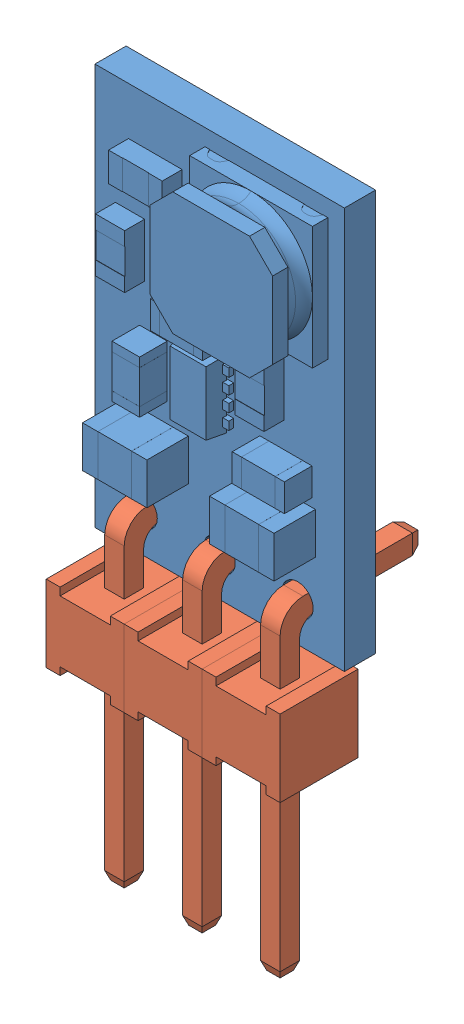
SolidWorks assembly step-up-voltage-regulator-u3v16fx_with_header, configuration Default. Lengths in mm.
Overall size (8.89 21.99 5.92).
2 component instances, 2 part files, 7 mates.
Components (placement in the parent):
- step-up-voltage-regulator-u3v16fx.step-1: step-up-voltage-regulator-u3v16fx.step [Default] at (-4.064 2.9064 0) size (8.13 13.08 2.82)
- Right angle pin header_03.step-1: Right angle pin header_03.step [Default] at (3.81 4.5 -2.6825) x (-1 0 0) z (0 1 0) size (7.62 5.54 10.5)
Mates (geometry in assembly coordinates):
- Symmetric1: symmetric aligned: plane of step-up-voltage-regulator-u3v16fx.step-1 through (4.064 2.9064 1.016) normal (1 0 0); plane of step-up-voltage-regulator-u3v16fx.step-1 through (-4.064 15.9874 1.016) normal (-1 0 0)
- Distance2: distance = 0.254 mm anti-aligned: plane of step-up-voltage-regulator-u3v16fx.step-1 through (-4.064 2.9064 1.016) normal (0 0 1); plane of Right angle pin header_03.step-1 through (2.8575 -17.398 1.27) normal (0 0 -1)
- Parallel2: parallel aligned: plane of step-up-voltage-regulator-u3v16fx.step-1 through (4.064 15.9874 1.016) normal (0 1 0)
- Coincident2: coincident anti-aligned: plane of step-up-voltage-regulator-u3v16fx.step-1 through (-4.064 2.9064 0) normal (0 0 -1)
- Symmetric2: symmetric aligned: plane of Right angle pin header_03.step-1 through (-3.81 0.25 2.8575) normal (-1 0 0); plane of Right angle pin header_03.step-1 through (3.81 0.25 2.8575) normal (1 0 0)
- Distance1: distance = 0.4064 mm anti-aligned: plane of step-up-voltage-regulator-u3v16fx.step-1 through (-4.064 2.9064 1.016) normal (0 -1 0); plane of Right angle pin header_03.step-1 through (1.27 2.5 -2.6825) normal (0 1 0)
- Coincident4: coincident anti-aligned: plane of Right angle pin header_03.step-1 through (3.81 0 -2.6825) normal (0 -1 0)
